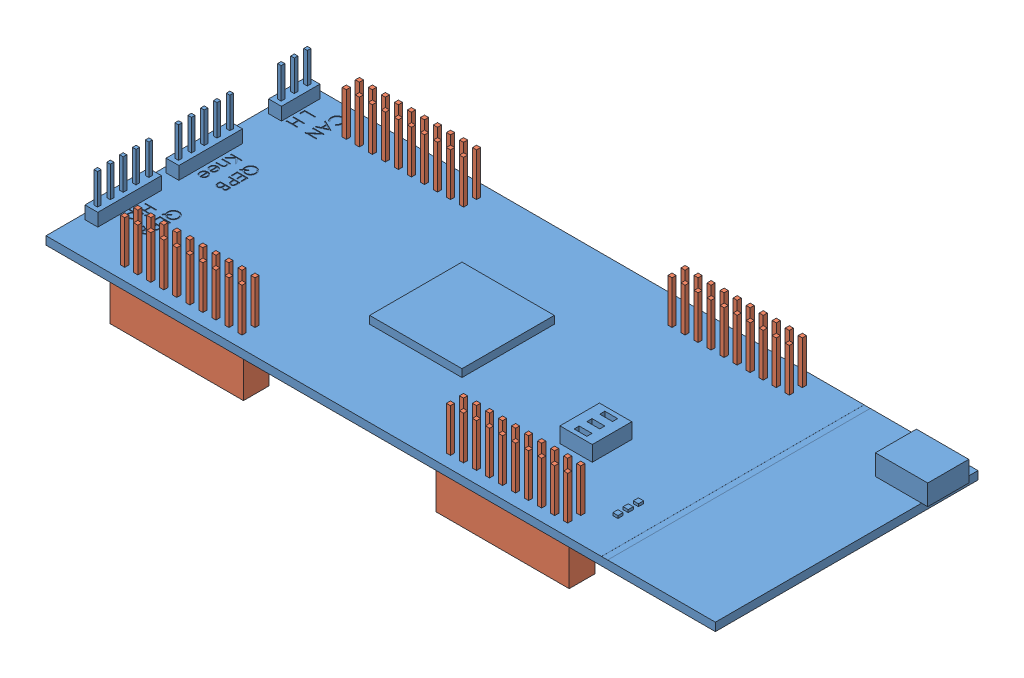
SolidWorks assembly launchpad, configuration Standard. Lengths in mm.
Overall size (131.7 18.6 51.2).
5 component instances, 2 part files, 12 mates.
Components (placement in the parent):
- launchpad-1: launchpad [Standard] at origin size (131.7 10.1 51.2)
- pin_header-1: pin_header [Standard] at (-41.25 0 -21.6) x (-1 0 0) z (0 0 1) size (26 18.5 5)
- pin_header-2: pin_header [Standard] at (-41.25 0 21.6) x (-1 0 0) z (0 0 1) size (26 18.5 5)
- pin_header-3: pin_header [Standard] at (22.25 0 -21.6) x (-1 0 0) z (0 0 1) size (26 18.5 5)
- pin_header-4: pin_header [Standard] at (22.25 0 21.6) x (-1 0 0) z (0 0 1) size (26 18.5 5)
Mates (geometry in assembly coordinates):
- Deckungsgleich1: coincident anti-aligned: plane of launchpad-1 through (0 0 0) normal (0 -1 0); plane of pin_header-1 through (-41.25 0 -21.6) normal (0 1 0)
- Abstand1: distance = 30 mm aligned: plane of pin_header-3 through (35.25 -8.5 -19.1) normal (1 0 0); plane of launchpad-1 through (65.25 1.6 25.6) normal (1 0 0)
- Deckungsgleich3: coincident anti-aligned: plane of launchpad-1 through (0 0 0) normal (0 -1 0); plane of pin_header-3 through (22.25 0 -21.6) normal (0 1 0)
- Deckungsgleich4: coincident anti-aligned: plane of launchpad-1 through (0 0 0) normal (0 -1 0); plane of pin_header-4 through (22.25 0 21.6) normal (0 1 0)
- Abstand2: distance = 30 mm aligned: plane of pin_header-4 through (35.25 -8.5 24.1) normal (1 0 0); plane of launchpad-1 through (65.25 1.6 25.6) normal (1 0 0)
- Abstand3: distance = 24.1 mm: plane of assembly through (0 0 0) normal (0 0 1); plane of assembly; plane of pin_header-3 through (35.25 -8.5 -24.1) normal (0 0 -1)
- Abstand4: distance = 24.1 mm aligned: plane of pin_header-4 through (35.25 -8.5 24.1) normal (0 0 1); plane of assembly through (0 0 0) normal (0 0 1)
- Deckungsgleich8: coincident aligned: plane of pin_header-1 through (-28.25 -8.5 -19.1) normal (0 0 1); plane of pin_header-3 through (35.25 -8.5 -19.1) normal (0 0 1)
- Deckungsgleich9: coincident aligned: plane of pin_header-2 through (-28.25 -8.5 19.1) normal (0 0 -1); plane of pin_header-4 through (35.25 -8.5 19.1) normal (0 0 -1)
- Deckungsgleich10: coincident anti-aligned: plane of launchpad-1 through (0 0 0) normal (0 -1 0); plane of pin_header-2 through (-41.25 0 21.6) normal (0 1 0)
- Deckungsgleich11: coincident aligned: plane of pin_header-1 through (-54.25 -8.5 -19.1) normal (-1 0 0); plane of pin_header-2 through (-54.25 -8.5 24.1) normal (-1 0 0)
- Abstand5: distance = 11 mm aligned: plane of launchpad-1 through (-65.25 1.6 25.6) normal (-1 0 0); plane of pin_header-1 through (-54.25 -8.5 -19.1) normal (-1 0 0)
